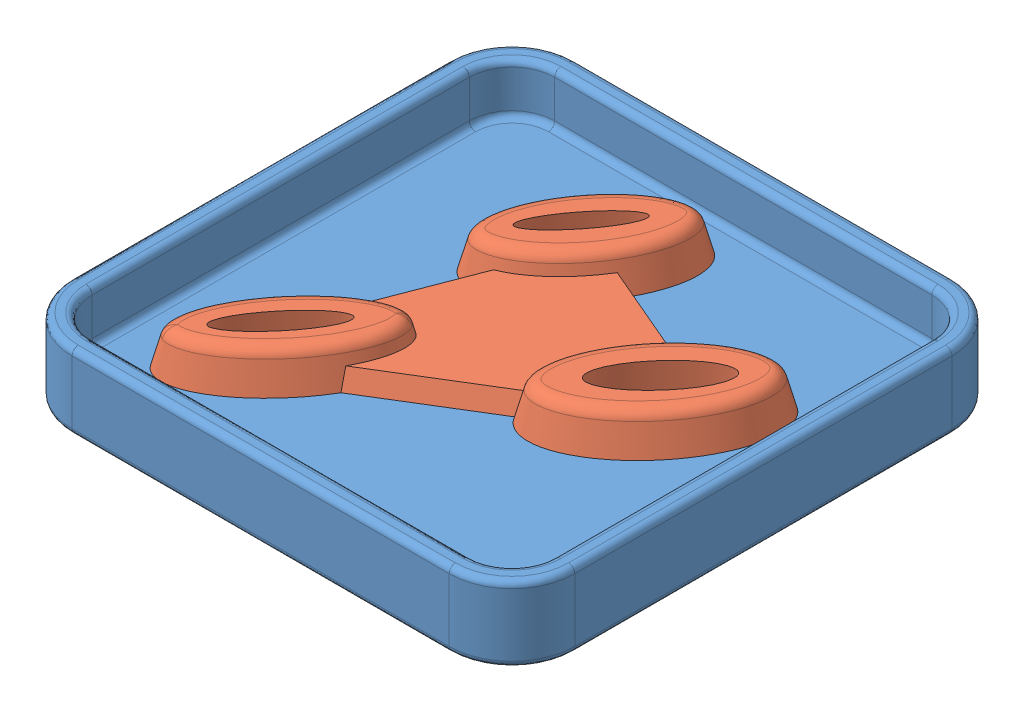
SolidWorks assembly Assem2, configuration Default. Lengths in mm.
Overall size (40 6 40).
2 component instances, 2 part files, 2 mates.
Components (placement in the parent):
- Tile-1: Tile [Default] at (15.8163 17.9112 30.2111) size (40 6 40)
- RemoteViewport-1: RemoteViewport [Default] at (15.7733 19.9112 29.8111) size (35 3.26 35)
Mates (geometry in assembly coordinates):
- Coincident1: coincident anti-aligned: plane of Tile-1 through (0.8163 19.9112 45.2111) normal (0 1 0); plane of RemoteViewport-1 through (15.7733 19.9112 29.8111) normal (0 -1 0)
- Coincident2: coincident anti-aligned: line of Tile-1 through (30.8163 19.9112 12.3111) axis (-1 0 0); line of RemoteViewport-1 through (-1.7267 19.9112 12.3111) axis (1 0 0)
